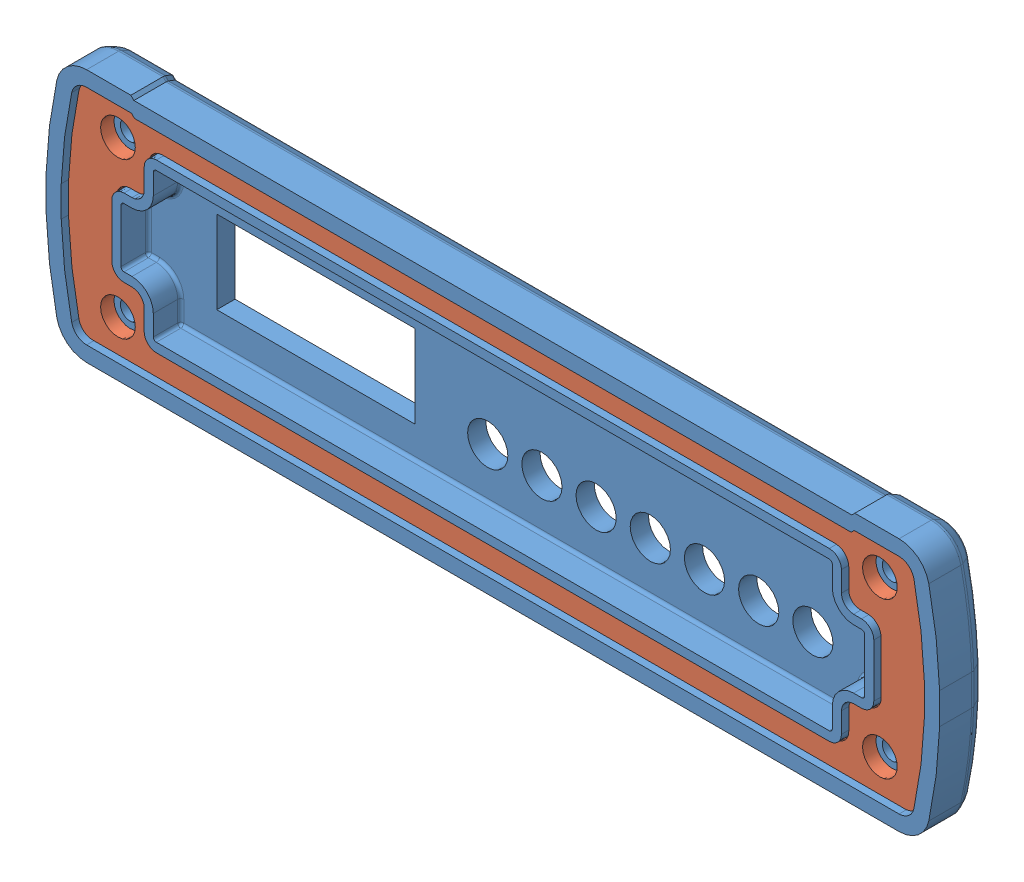
SolidWorks assembly hbexn23362, configuration Default. Lengths in mm.
Overall size (146.6 41.6 7.5).
5 component instances, 4 part files, 0 mates.
Components (placement in the parent):
- EXN-23362M-B-1: EXN-23362M-B [Default] at origin size (140 35.42 200.01) (hidden)
- EXN-23362M-P-1: EXN-23362M-P [Default] at (312.1179 -644.6848 161) size (146.6 41.6 7.5) (hidden)
- EXN-23362M-P_Right-1: EXN-23362M-P_Right [Default] at (972.3862 -644.6848 39) x (-1 0 0) z (0 0 -1) size (146.6 41.6 7.5)
- EXN-23383-GSK-1: EXN-23383-GSK [Default] at (312.1179 -644.6848 -31) size (141.2 36.2 3)
- EXN-23383-GSK-2: EXN-23383-GSK [Default] at (312.1179 -644.6848 168) size (141.2 36.2 3) (hidden)
